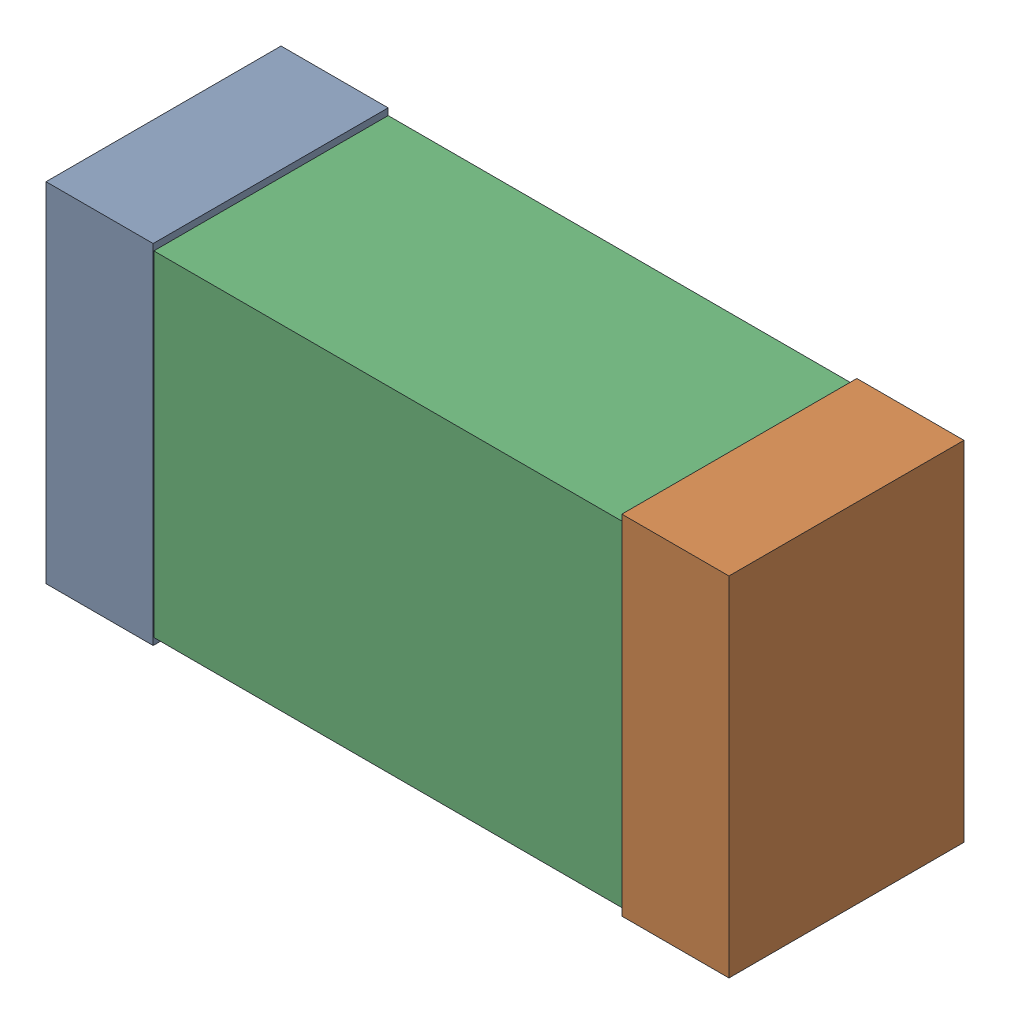
SolidWorks assembly C44, configuration Default. Lengths in mm.
Overall size (1.02 0.52 0.35).
6 component instances, 2 part files, 0 mates.
Components (placement in the parent):
- 870940480-1: 870940480 [Default] at (29.084 26.6678 0) size (0.16 0.52 0.35)
  - Extruded-1: Extruded [Default] at origin size (0.16 0.52 0.35)
- 870940480-2: 870940480 [Default] at (29.944 26.6678 0) size (0.16 0.52 0.35)
  - Extruded-1: Extruded [Default] at origin size (0.16 0.52 0.35)
- 870940640-1: 870940640 [Default] at (29.514 26.6678 0) size (1 0.5 0.35)
  - Extruded_2-1: Extruded_2 [Default] at origin size (1 0.5 0.35)
